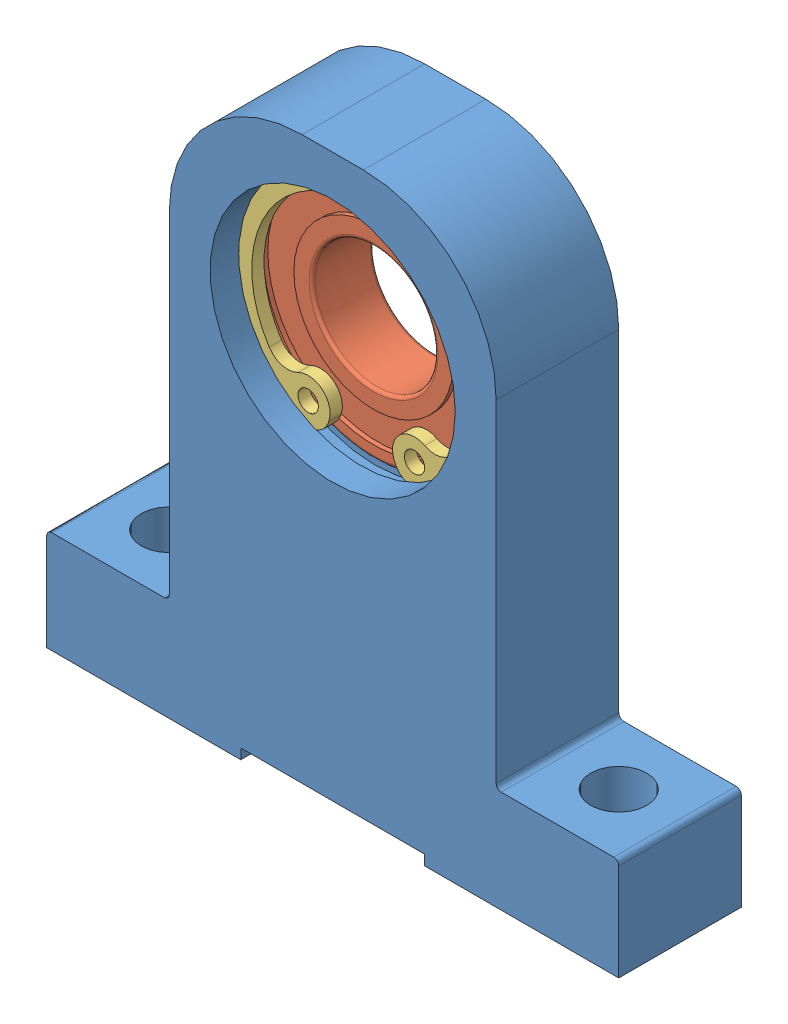
SolidWorks assembly C-BGHKAX6901ZZ-40, configuration Default. Lengths in mm.
Overall size (56 56 12).
3 component instances, 3 part files, 6 mates.
Components (placement in the parent):
- Housing_C-BGHKAX6901ZZ-40-1: Housing_C-BGHKAX6901ZZ-40 [C-BGHKAX6901ZZ-40] at (-7.2092 4.9372 -5.5) size (56 56 12)
- 6901ZZ-2: 6901ZZ [Default] at (-7.2092 4.9372 -3.5) x (0 0 1) z (-1 0 0) size (6 24 24)
- RTWN24-1: RTWN24 [Default] at (-7.2092 4.9372 3.1) x (0 0 -1) z (1 0 0) size (1.2 23.88 25.2)
Mates (geometry in assembly coordinates):
- Distance1: distance = 2 mm: plane of 6901ZZ-2 through (-7.2092 4.9372 -3.5) normal (0 0 1); plane of Housing_C-BGHKAX6901ZZ-40-1 through (-7.2092 4.9372 -5.5) normal (0 0 1)
- Coincident4: coincident: plane of Housing_C-BGHKAX6901ZZ-40-1 through (-7.2092 4.9372 -5.5) normal (0 1 0); plane of 6901ZZ-2
- Concentric1: concentric: cylinder of Housing_C-BGHKAX6901ZZ-40-1 through (-7.2092 4.9372 -3.5) axis (0 0 1) radius 12; cylinder of 6901ZZ-2 through (-7.2092 4.9372 2.5) axis (0 0 -1) radius 6
- Coincident5: coincident: plane of 6901ZZ-2 through (-7.2092 11.2372 2.5) normal (0 0 1); plane of RTWN24-1 through (-12.323 -4.3477 2.5) normal (0 0 -1)
- Coincident6: coincident: plane of 6901ZZ-2 through (-7.2092 4.9372 -3.5) normal (-1 0 0); plane of RTWN24-1 through (-7.2092 4.9372 3.1) normal (1 0 0)
- Coincident7: coincident: plane of 6901ZZ-2; plane of RTWN24-1
